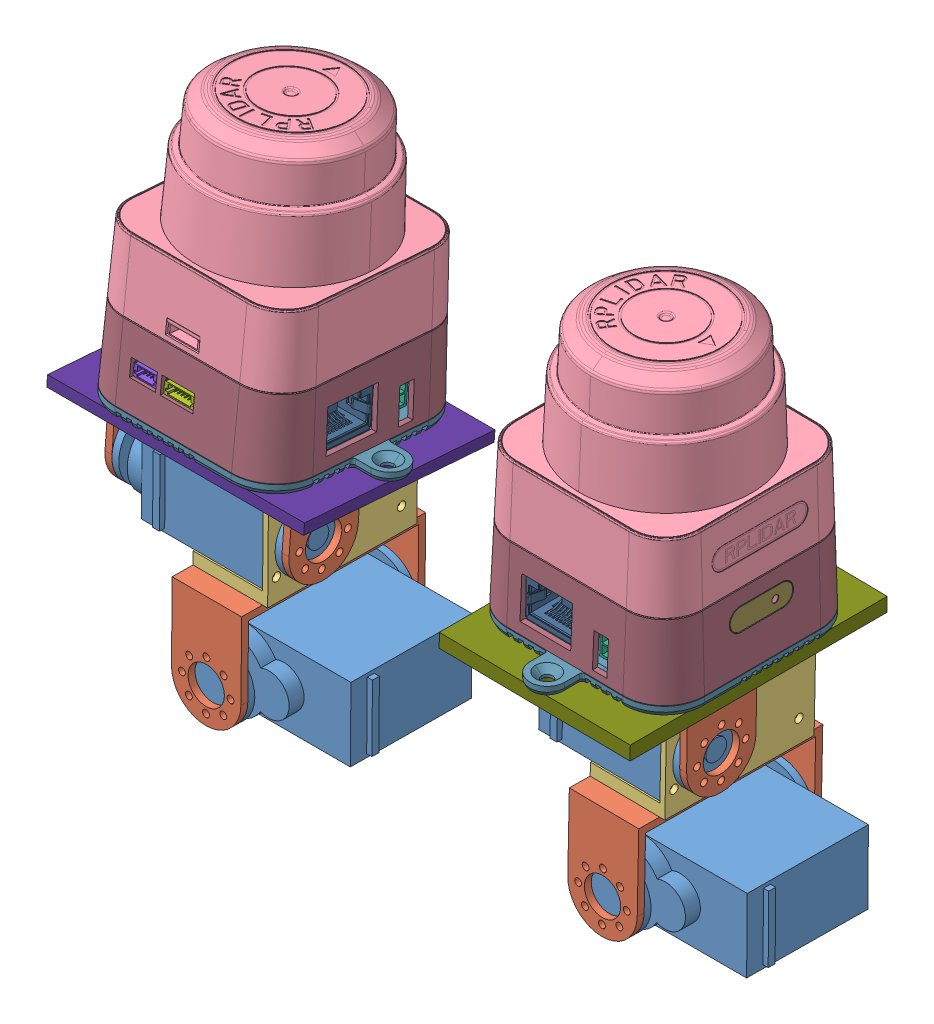
SolidWorks assembly SLAM_Platform_All, configuration 預設. Lengths in mm.
Overall size (208.91 156.53 114.08).
42 component instances, 17 part files, 0 mates.
Components (placement in the parent):
- SLAM_Platform_M2M1_1-1: SLAM_Platform_M2M1_1 [預設] at (-38.1287 -70.2469 89.1269) size (109.59 148.91 97.37) (flexible)
  - KRS_786-1: KRS_786 [預設] at (-28.6478 -1.4384 68.5627) x (1 0 0) z (0 -0.008727 -0.999962) size (44 21 49.5)
  - KRS_786-2: KRS_786 [預設] at (-63.1192 35.2145 52.8422) x (0 -0.008727 -0.999962) z (0.999932 -0.011695 0.000102) size (44 21 49.5)
  - MotorRotate-1: MotorRotate [預設] at (-38.3905 20.4249 52.9713) x (0 -0.008727 -0.999962) z (-0.011695 -0.999894 0.008726) size (53 20 32)
  - MotorRotate2-1: MotorRotate2 [預設] at (-38.3905 20.4249 52.9713) x (0.999932 -0.011695 0.000102) z (0.011695 0.999894 -0.008726) size (21.5 43 25)
  - MotorRotate-2: MotorRotate [預設] at (-47.463 57.1202 62.8802) x (-0.999932 0.011695 -0.000102) z (-0.011694 -0.99993 -0.001669) size (53 20 32)
  - SLAMTEC MAPPER M2M1_IGS-1: SLAMTEC MAPPER M2M1_IGS [預設] at (-37.5374 84.906 62.9277) x (0.000122 0.001668 -0.999999) z (-0.011694 -0.99993 -0.001669) size (97.23 108.71 74.91)
    - SLAMTEC MAPPER M2M1_IGS(2)^SLAMTEC MAPPER M2M1_IGS-1: SLAMTEC MAPPER M2M1_IGS(2)^SLAMTEC MAPPER M2M1_IGS [預設] at origin size (97.23 108.71 74.91) (virtual)
      - rplidar-s1m1-r1^SLAMTEC MAPPER M2M1_IGS(2)_SLAMTEC MAPPER M2M1_IGS-1: rplidar-s1m1-r1^SLAMTEC MAPPER M2M1_IGS(2)_SLAMTEC MAPPER M2M1_IGS [預設] at origin size (97.23 108.71 51.5) (virtual)
      - 厙釐曹揤 ^SLAMTEC MAPPER M2M1_IGS(2)_SLAMTEC MAPPER M2M1_IGS-1: 厙釐曹揤 ^SLAMTEC MAPPER M2M1_IGS(2)_SLAMTEC MAPPER M2M1_IGS [預設] at (-6.25 -5.803 2.75) x (0 1 0) z (0 0 1) size (12.81 9.31 5.66) (virtual)
      - DC脣釱^SLAMTEC MAPPER M2M1_IGS(2)_SLAMTEC MAPPER M2M1_IGS-1: DC脣釱^SLAMTEC MAPPER M2M1_IGS(2)_SLAMTEC MAPPER M2M1_IGS [預設] at (-21.55 9.972 13.335) x (0 -1 0) z (-1 0 0) size (7.16 11.96 12.25) (virtual)
      - User Library-JST - SM06B-SRSS-TB (SH SERIES - 1_0mm PITCH WIRE-TO-BOARD, SMT, RA)^SLAMTEC MAPPER M2M1_IGS(2)_SLAMTEC MAPPER M2M1_IGS-1: User Library-JST - SM06B-SRSS-TB (SH SERIES - 1_0mm PITCH WIRE-TO-BOARD, SMT, RA)^SLAMTEC MAPPER M2M1_IGS(2)_SLAMTEC MAPPER M2M1_IGS [預設] at (0 -23.25 9.4) x (1 0 0) z (0 -1 0) size (8.81 3.31 4.96) (virtual)
      - User Library-JST - SM04B-SRSS-TB (SH SERIES - 1_0mm PITCH WIRE-TO-BOARD, SMT, RA)^SLAMTEC MAPPER M2M1_IGS(2)_SLAMTEC MAPPER M2M1_IGS-1: User Library-JST - SM04B-SRSS-TB (SH SERIES - 1_0mm PITCH WIRE-TO-BOARD, SMT, RA)^SLAMTEC MAPPER M2M1_IGS(2)_SLAMTEC MAPPER M2M1_IGS [預設] at (9.8 -23.25 9.4) x (1 0 0) z (0 -1 0) size (6.91 3.31 4.96) (virtual)
      - 綻蟯邧伎LED^SLAMTEC MAPPER M2M1_IGS(2)_SLAMTEC MAPPER M2M1_IGS-1: 綻蟯邧伎LED^SLAMTEC MAPPER M2M1_IGS(2)_SLAMTEC MAPPER M2M1_IGS [預設] at (-4 23.52 7.9) x (1 0 0) z (0 1 0) size (3.21 1.01 1.49) (virtual)
      - RJ45 1X1 SMT 8P8C-B脣釱 LCP窪遠悵__J17 DJ^SLAMTEC MAPPER M2M1_IGS(2)_SLAMTEC MAPPER M2M1_IGS-1: RJ45 1X1 SMT 8P8C-B脣釱 LCP窪遠悵__J17 DJ^SLAMTEC MAPPER M2M1_IGS(2)_SLAMTEC MAPPER M2M1_IGS [預設] at (-12.775 2.597 6.35) x (0 -1 0) z (0 0 -1) size (18.41 15.1 11.62) (virtual)
      - K2-1823SA葩弇羲壽^SLAMTEC MAPPER M2M1_IGS(2)_SLAMTEC MAPPER M2M1_IGS-1: K2-1823SA葩弇羲壽^SLAMTEC MAPPER M2M1_IGS(2)_SLAMTEC MAPPER M2M1_IGS [預設] at (4 23.75 7.1) x (-1 0 0) z (0 0 1) size (4.01 3.21 1.81) (virtual)
      - BAT_COVER1^SLAMTEC MAPPER M2M1_IGS(2)_SLAMTEC MAPPER M2M1_IGS-1: BAT_COVER1^SLAMTEC MAPPER M2M1_IGS(2)_SLAMTEC MAPPER M2M1_IGS [預設] at (0 -0.1187 -3.4) x (1 0 0) z (0 1 0) size (18.02 6.02 0.42) (virtual)
      - Mapper2-奻褲^SLAMTEC MAPPER M2M1_IGS(2)_SLAMTEC MAPPER M2M1_IGS-1: Mapper2-奻褲^SLAMTEC MAPPER M2M1_IGS(2)_SLAMTEC MAPPER M2M1_IGS [預設] x (1 0 0) z (0 1 0) size (57.05 23.13 57.05) (virtual)
      - MP2-底板-1031^SLAMTEC MAPPER M2M1_IGS(2)_SLAMTEC MAPPER M2M1_IGS-1: MP2-底板-1031^SLAMTEC MAPPER M2M1_IGS(2)_SLAMTEC MAPPER M2M1_IGS [預設] at (0 0 -1.6) x (1 0 0) z (0 1 0) size (77.12 5.51 57) (virtual)
      - Thermal pad_pad^SLAMTEC MAPPER M2M1_IGS(2)_SLAMTEC MAPPER M2M1_IGS-1: Thermal pad_pad^SLAMTEC MAPPER M2M1_IGS(2)_SLAMTEC MAPPER M2M1_IGS [預設] at (2 2.4517 21.4) x (-1 0 0) z (0 1 0) size (24.01 1.76 15.01) (virtual)
  - M2M1_base-1: M2M1_base [預設] at (-37.9169 61.0088 62.8878) x (-0.000122 -0.001668 0.999999) z (-0.011694 -0.99993 -0.001669) size (74 55 4)
- SLAM_Platform_M2M1_2-1: SLAM_Platform_M2M1_2 [預設] at (-31.8059 -77.575 1.8509) size (97.47 147.83 109.36) (flexible)
  - KRS_786-1: KRS_786 [預設] at (-139.2107 11.3616 165.7373) x (1 0 0) z (0 -0.008727 -0.999962) size (44 21 49.5)
  - KRS_786-2: KRS_786 [預設] at (-174.102 47.7318 150.0193) x (0 -0.008727 -0.999962) z (1 -0.00024 0.000002) size (44 21 49.5)
  - MotorRotate-1: MotorRotate [預設] at (-149.2055 33.2264 150.1459) x (0 -0.008727 -0.999962) z (-0.00024 -0.999962 0.008727) size (53 20 32)
  - MotorRotate2-1: MotorRotate2 [預設] at (-149.2055 33.2264 150.1459) x (1 -0.00024 0.000002) z (0.00024 0.999962 -0.008727) size (21.5 43 25)
  - M2M1_base2-1: M2M1_base2 [預設] at (-149.196 72.741 158.1212) x (-1 0.00024 -0.000002) z (-0.000239 -0.997115 0.07591) size (74 55 3)
  - MotorRotate-2: MotorRotate [預設] at (-158.6967 69.7519 158.3489) x (-1 0.00024 -0.000002) z (-0.000239 -0.997115 0.07591) size (53 20 32)
  - SLAMTEC MAPPER M2M1_IGS-1: SLAMTEC MAPPER M2M1_IGS [預設] at (-149.1903 96.572 156.307) x (-1 0.00024 -0.000002) z (-0.000239 -0.997115 0.07591) size (97.23 108.71 74.91)
    - SLAMTEC MAPPER M2M1_IGS(2)^SLAMTEC MAPPER M2M1_IGS-1: SLAMTEC MAPPER M2M1_IGS(2)^SLAMTEC MAPPER M2M1_IGS [預設] at origin size (97.23 108.71 74.91) (virtual)
      - rplidar-s1m1-r1^SLAMTEC MAPPER M2M1_IGS(2)_SLAMTEC MAPPER M2M1_IGS-1: rplidar-s1m1-r1^SLAMTEC MAPPER M2M1_IGS(2)_SLAMTEC MAPPER M2M1_IGS [預設] at origin size (97.23 108.71 51.5) (virtual)
      - 厙釐曹揤 ^SLAMTEC MAPPER M2M1_IGS(2)_SLAMTEC MAPPER M2M1_IGS-1: 厙釐曹揤 ^SLAMTEC MAPPER M2M1_IGS(2)_SLAMTEC MAPPER M2M1_IGS [預設] at (-6.25 -5.803 2.75) x (0 1 0) z (0 0 1) size (12.81 9.31 5.66) (virtual)
      - DC脣釱^SLAMTEC MAPPER M2M1_IGS(2)_SLAMTEC MAPPER M2M1_IGS-1: DC脣釱^SLAMTEC MAPPER M2M1_IGS(2)_SLAMTEC MAPPER M2M1_IGS [預設] at (-21.55 9.972 13.335) x (0 -1 0) z (-1 0 0) size (7.16 11.96 12.25) (virtual)
      - User Library-JST - SM06B-SRSS-TB (SH SERIES - 1_0mm PITCH WIRE-TO-BOARD, SMT, RA)^SLAMTEC MAPPER M2M1_IGS(2)_SLAMTEC MAPPER M2M1_IGS-1: User Library-JST - SM06B-SRSS-TB (SH SERIES - 1_0mm PITCH WIRE-TO-BOARD, SMT, RA)^SLAMTEC MAPPER M2M1_IGS(2)_SLAMTEC MAPPER M2M1_IGS [預設] at (0 -23.25 9.4) x (1 0 0) z (0 -1 0) size (8.81 3.31 4.96) (virtual)
      - User Library-JST - SM04B-SRSS-TB (SH SERIES - 1_0mm PITCH WIRE-TO-BOARD, SMT, RA)^SLAMTEC MAPPER M2M1_IGS(2)_SLAMTEC MAPPER M2M1_IGS-1: User Library-JST - SM04B-SRSS-TB (SH SERIES - 1_0mm PITCH WIRE-TO-BOARD, SMT, RA)^SLAMTEC MAPPER M2M1_IGS(2)_SLAMTEC MAPPER M2M1_IGS [預設] at (9.8 -23.25 9.4) x (1 0 0) z (0 -1 0) size (6.91 3.31 4.96) (virtual)
      - 綻蟯邧伎LED^SLAMTEC MAPPER M2M1_IGS(2)_SLAMTEC MAPPER M2M1_IGS-1: 綻蟯邧伎LED^SLAMTEC MAPPER M2M1_IGS(2)_SLAMTEC MAPPER M2M1_IGS [預設] at (-4 23.52 7.9) x (1 0 0) z (0 1 0) size (3.21 1.01 1.49) (virtual)
      - RJ45 1X1 SMT 8P8C-B脣釱 LCP窪遠悵__J17 DJ^SLAMTEC MAPPER M2M1_IGS(2)_SLAMTEC MAPPER M2M1_IGS-1: RJ45 1X1 SMT 8P8C-B脣釱 LCP窪遠悵__J17 DJ^SLAMTEC MAPPER M2M1_IGS(2)_SLAMTEC MAPPER M2M1_IGS [預設] at (-12.775 2.597 6.35) x (0 -1 0) z (0 0 -1) size (18.41 15.1 11.62) (virtual)
      - K2-1823SA葩弇羲壽^SLAMTEC MAPPER M2M1_IGS(2)_SLAMTEC MAPPER M2M1_IGS-1: K2-1823SA葩弇羲壽^SLAMTEC MAPPER M2M1_IGS(2)_SLAMTEC MAPPER M2M1_IGS [預設] at (4 23.75 7.1) x (-1 0 0) z (0 0 1) size (4.01 3.21 1.81) (virtual)
      - BAT_COVER1^SLAMTEC MAPPER M2M1_IGS(2)_SLAMTEC MAPPER M2M1_IGS-1: BAT_COVER1^SLAMTEC MAPPER M2M1_IGS(2)_SLAMTEC MAPPER M2M1_IGS [預設] at (0 -0.1187 -3.4) x (1 0 0) z (0 1 0) size (18.02 6.02 0.42) (virtual)
      - Mapper2-奻褲^SLAMTEC MAPPER M2M1_IGS(2)_SLAMTEC MAPPER M2M1_IGS-1: Mapper2-奻褲^SLAMTEC MAPPER M2M1_IGS(2)_SLAMTEC MAPPER M2M1_IGS [預設] x (1 0 0) z (0 1 0) size (57.05 23.13 57.05) (virtual)
      - MP2-底板-1031^SLAMTEC MAPPER M2M1_IGS(2)_SLAMTEC MAPPER M2M1_IGS-1: MP2-底板-1031^SLAMTEC MAPPER M2M1_IGS(2)_SLAMTEC MAPPER M2M1_IGS [預設] at (0 0 -1.6) x (1 0 0) z (0 1 0) size (77.12 5.51 57) (virtual)
      - Thermal pad_pad^SLAMTEC MAPPER M2M1_IGS(2)_SLAMTEC MAPPER M2M1_IGS-1: Thermal pad_pad^SLAMTEC MAPPER M2M1_IGS(2)_SLAMTEC MAPPER M2M1_IGS [預設] at (2 2.4517 21.4) x (-1 0 0) z (0 1 0) size (24.01 1.76 15.01) (virtual)
